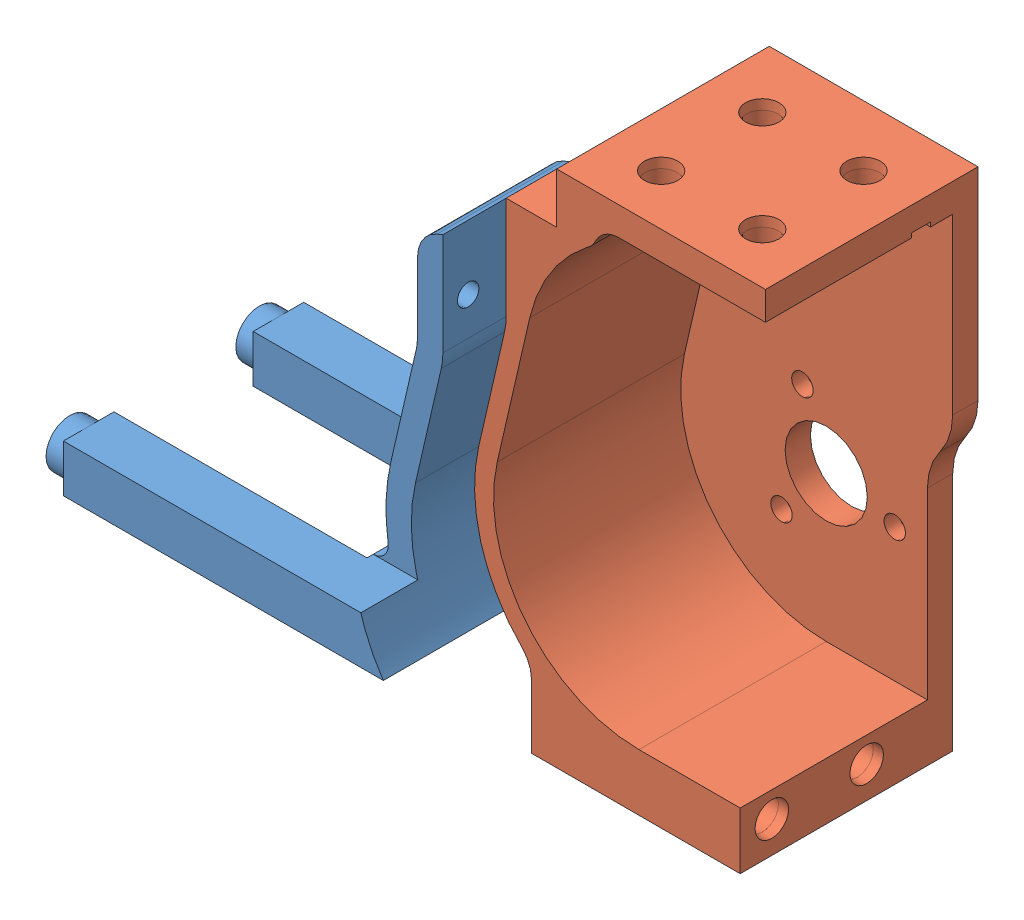
SolidWorks assembly testfit, configuration Default. Lengths in mm.
Overall size (95 82 52.6).
2 component instances, 2 part files, 3 mates.
Components (placement in the parent):
- Front bumper mount-1: Front bumper mount [Default] at (3.7076 -33.1683 -8.953) size (54 56.75 38)
- Front Drivemount_R-1: Front Drivemount_R [Default] at (75.7076 -22.1683 -8.953) x (0 0 -1) z (1 0 0) size (33.6 82 46)
Mates (geometry in assembly coordinates):
- Concentric3: concentric: cylinder of Front bumper mount-1 through (75.7076 -22.1683 -27.953) axis (0 0 1) radius 26; cylinder of Front Drivemount_R-1 through (75.7076 -22.1683 -140.7672) axis (0 0 1) radius 26
- Parallel4: parallel: plane of Front bumper mount-1 through (3.7076 -36.9183 -8.953) normal (0 -1 0); plane of Front Drivemount_R-1 through (91.7076 -54.1683 -140.7672) normal (0 -1 0)
- Distance1: distance = 10 mm aligned: plane of Front bumper mount-1 through (75.7076 -22.1683 1.047) normal (0 0 1); plane of Front Drivemount_R-1 through (75.7076 -22.1683 -8.953) normal (0 0 1)
